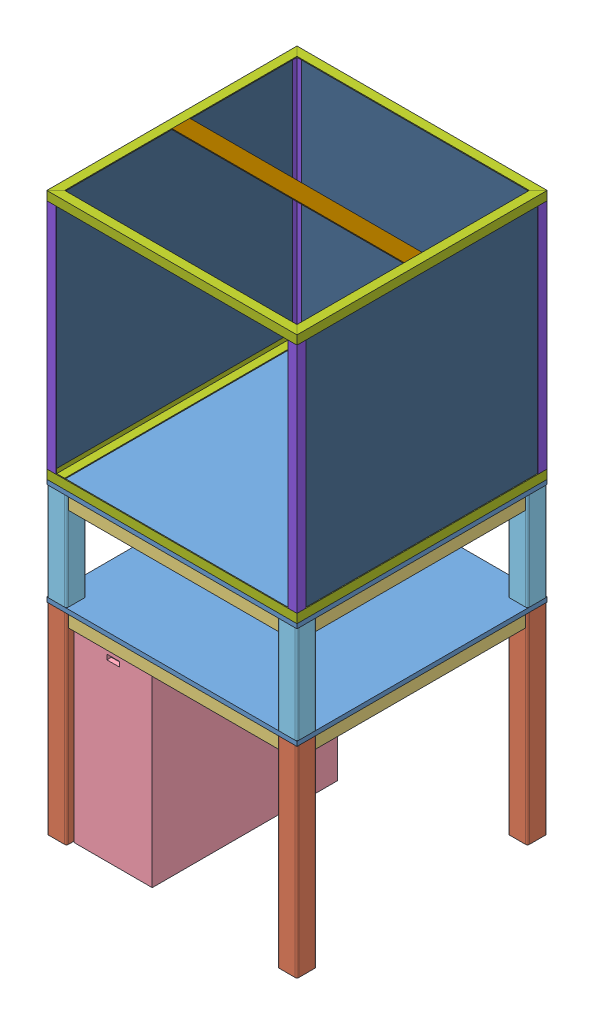
SolidWorks assembly Stolik, configuration Domyślna. Lengths in mm.
Overall size (560 1248 560).
60 component instances, 11 part files, 43 mates.
Components (placement in the parent):
- blat-1: blat [Domyślna] at (-5.6516 -3.6643 0) size (560 10 560)
- noga^Stolik-1: noga^Stolik [Domyślna] at (-5.6516 -3.6643 0) x (-1 0 0) z (0 -1 0) size (44 44 450) (virtual)
- noga^Stolik-2: noga^Stolik [Domyślna] at (-5.6516 -3.6643 0) x (0 0 -1) z (0 -1 0) size (44 44 450) (virtual)
- noga^Stolik-3: noga^Stolik [Domyślna] at (-5.6516 -3.6643 0) x (1 0 0) z (0 -1 0) size (44 44 450) (virtual)
- noga^Stolik-4: noga^Stolik [Domyślna] at (-5.6516 -3.6643 0) x (0 0 1) z (0 -1 0) size (44 44 450) (virtual)
- krokwia^Stolik-1: krokwia^Stolik [Domyślna] at (-5.6516 -3.6643 0) x (-1 0 0) z (0 -1 0) size (472 10 30) (virtual)
- krokwia^Stolik-2: krokwia^Stolik [Domyślna] at (-5.6516 -3.6643 0) x (0 0 -1) z (0 -1 0) size (472 10 30) (virtual)
- krokwia^Stolik-3: krokwia^Stolik [Domyślna] at (-5.6516 -3.6643 0) x (1 0 0) z (0 -1 0) size (472 10 30) (virtual)
- krokwia^Stolik-4: krokwia^Stolik [Domyślna] at (-5.6516 -3.6643 0) x (0 0 1) z (0 -1 0) size (472 10 30) (virtual)
- Część4^Stolik-1: Część4^Stolik [Domyślna] at (98.5779 -453.6643 -106.3674) x (-1 0 0) z (0 -1 0) size (175 415 415) (virtual)
- blat-2: blat [Domyślna] at (-5.6516 224.3357 0) size (560 10 560)
- Noga_gorna^Stolik-1: Noga_gorna^Stolik [Domyślna] at (-5.6516 224.3357 0) x (-1 0 0) z (0 -1 0) size (44 44 218) (virtual)
- Noga_gorna^Stolik-2: Noga_gorna^Stolik [Domyślna] at (-5.6516 224.3357 0) x (0 0 -1) z (0 -1 0) size (44 44 218) (virtual)
- Noga_gorna^Stolik-3: Noga_gorna^Stolik [Domyślna] at (-5.6516 224.3357 0) x (1 0 0) z (0 -1 0) size (44 44 218) (virtual)
- Noga_gorna^Stolik-4: Noga_gorna^Stolik [Domyślna] at (-5.6516 224.3357 0) x (0 0 1) z (0 -1 0) size (44 44 218) (virtual)
- krokwia^Stolik-5: krokwia^Stolik [Domyślna] at (-5.6516 224.3357 0) x (-1 0 0) z (0 -1 0) size (472 10 30) (virtual)
- krokwia^Stolik-6: krokwia^Stolik [Domyślna] at (-5.6516 224.3357 0) x (0 0 -1) z (0 -1 0) size (472 10 30) (virtual)
- krokwia^Stolik-7: krokwia^Stolik [Domyślna] at (-5.6516 224.3357 0) x (1 0 0) z (0 -1 0) size (472 10 30) (virtual)
- krokwia^Stolik-8: krokwia^Stolik [Domyślna] at (-5.6516 224.3357 0) x (0 0 1) z (0 -1 0) size (472 10 30) (virtual)
- Katownik^Stolik-1: Katownik^Stolik [Domyślna] at (-271.6516 194.3357 -236) x (0 0 1) z (0 1 0) size (20 21 15) (virtual)
- Katownik^Stolik-4: Katownik^Stolik [Domyślna] at (-241.6516 194.3357 -266) x (0 0 1) z (0 1 0) size (20 21 15) (virtual)
- Katownik^Stolik-11: Katownik^Stolik [Domyślna] at (7.5 224.3357 -266) x (0 -1 0) z (-1 0 0) size (20 21 15) (virtual)
- Katownik^Stolik-12: Katownik^Stolik [Domyślna] at (260.3484 224.3357 13.1516) x (0 -1 0) z (0 0 -1) size (20 21 15) (virtual)
- Katownik^Stolik-13: Katownik^Stolik [Domyślna] at (-18.8031 224.3357 266) x (0 -1 0) z (1 0 0) size (20 21 15) (virtual)
- Katownik^Stolik-14: Katownik^Stolik [Domyślna] at (-271.6516 224.3357 -13.1516) x (0 -1 0) z (0 0 1) size (20 21 15) (virtual)
- Katownik^Stolik-15: Katownik^Stolik [Domyślna] at (230.3484 194.3357 -266) x (-1 0 0) z (0 1 0) size (20 21 15) (virtual)
- Katownik^Stolik-16: Katownik^Stolik [Domyślna] at (260.3484 194.3357 236) x (0 0 -1) z (0 1 0) size (20 21 15) (virtual)
- Katownik^Stolik-17: Katownik^Stolik [Domyślna] at (-241.6516 194.3357 266) x (1 0 0) z (0 1 0) size (20 21 15) (virtual)
- Katownik^Stolik-18: Katownik^Stolik [Domyślna] at (260.3484 194.3357 -236) x (-1 0 0) z (0 1 0) size (20 21 15) (virtual)
- Katownik^Stolik-19: Katownik^Stolik [Domyślna] at (230.3484 194.3357 266) x (0 0 -1) z (0 1 0) size (20 21 15) (virtual)
- Katownik^Stolik-20: Katownik^Stolik [Domyślna] at (-271.6516 194.3357 236) x (1 0 0) z (0 1 0) size (20 21 15) (virtual)
- Katownik^Stolik-21: Katownik^Stolik [Domyślna] at (7.5 -3.6643 -266) x (0 -1 0) z (-1 0 0) size (20 21 15) (virtual)
- Katownik^Stolik-22: Katownik^Stolik [Domyślna] at (-271.6516 -33.6643 -236) x (0 0 1) z (0 1 0) size (20 21 15) (virtual)
- Katownik^Stolik-23: Katownik^Stolik [Domyślna] at (-241.6516 -33.6643 -266) x (0 0 1) z (0 1 0) size (20 21 15) (virtual)
- Katownik^Stolik-24: Katownik^Stolik [Domyślna] at (260.3484 -3.6643 13.1516) x (0 -1 0) z (0 0 -1) size (20 21 15) (virtual)
- Katownik^Stolik-25: Katownik^Stolik [Domyślna] at (-18.8031 -3.6643 266) x (0 -1 0) z (1 0 0) size (20 21 15) (virtual)
- Katownik^Stolik-26: Katownik^Stolik [Domyślna] at (-271.6516 -3.6643 -13.1516) x (0 -1 0) z (0 0 1) size (20 21 15) (virtual)
- Katownik^Stolik-27: Katownik^Stolik [Domyślna] at (230.3484 -33.6643 -266) x (-1 0 0) z (0 1 0) size (20 21 15) (virtual)
- Katownik^Stolik-28: Katownik^Stolik [Domyślna] at (260.3484 -33.6643 236) x (0 0 -1) z (0 1 0) size (20 21 15) (virtual)
- Katownik^Stolik-29: Katownik^Stolik [Domyślna] at (-241.6516 -33.6643 266) x (1 0 0) z (0 1 0) size (20 21 15) (virtual)
- Katownik^Stolik-30: Katownik^Stolik [Domyślna] at (260.3484 -33.6643 -236) x (-1 0 0) z (0 1 0) size (20 21 15) (virtual)
- Katownik^Stolik-31: Katownik^Stolik [Domyślna] at (230.3484 -33.6643 266) x (0 0 -1) z (0 1 0) size (20 21 15) (virtual)
- Katownik^Stolik-32: Katownik^Stolik [Domyślna] at (-271.6516 -33.6643 236) x (1 0 0) z (0 1 0) size (20 21 15) (virtual)
- Kopia Prusa MK3^Stolik-1: Kopia Prusa MK3^Stolik [Domyślna] at (-197.6615 426.9086 147.2152) x (1 0 0) z (0 1 0) size (440.6 497.98 377.63) (hidden, virtual)
- Część3^Stolik-1: Część3^Stolik [Domyślna] at origin size (20 20 560) (virtual)
- Część3^Stolik-2: Część3^Stolik [Domyślna] at (-5.6516 0 5.6516) x (0 0 1) z (-1 0 0) size (20 20 560) (virtual)
- Część3^Stolik-3: Część3^Stolik [Domyślna] at (-11.3031 0 0) x (-1 0 0) z (0 0 -1) size (20 20 560) (virtual)
- Część3^Stolik-4: Część3^Stolik [Domyślna] at (-5.6516 0 -5.6516) x (0 0 -1) z (1 0 0) size (20 20 560) (virtual)
- Część3^Stolik-5: Część3^Stolik [Domyślna] at (-5.6516 1028.6714 5.6516) x (0 0 1) z (1 0 0) size (20 20 560) (virtual)
- Część3^Stolik-6: Część3^Stolik [Domyślna] at (0 1028.6714 0) x (1 0 0) z (0 0 -1) size (20 20 560) (virtual)
- Część3^Stolik-7: Część3^Stolik [Domyślna] at (-11.3031 1028.6714 0) x (-1 0 0) z (0 0 1) size (20 20 560) (virtual)
- Część3^Stolik-8: Część3^Stolik [Domyślna] at (-5.6516 1028.6714 -5.6516) x (0 0 -1) z (-1 0 0) size (20 20 560) (virtual)
- Część5^Stolik-1: Część5^Stolik [Domyślna] at (0 254.3357 0) x (1 0 0) z (0 1 0) size (20 20 520) (virtual)
- Część5^Stolik-2: Część5^Stolik [Domyślna] at (-5.6516 254.3357 5.6516) x (0 0 1) z (0 1 0) size (20 20 520) (virtual)
- Część5^Stolik-3: Część5^Stolik [Domyślna] at (-11.3031 254.3357 0) x (-1 0 0) z (0 1 0) size (20 20 520) (virtual)
- Część5^Stolik-4: Część5^Stolik [Domyślna] at (-5.6516 254.3357 -5.6516) x (0 0 -1) z (0 1 0) size (20 20 520) (virtual)
- Część6^Stolik-1: Część6^Stolik [Domyślna] at (274.3484 1028.6714 0) x (0 0 1) z (1 0 0) size (40 2 520) (virtual)
- Część7^Stolik-1: Część7^Stolik [Domyślna] at (-283.6516 0 0) x (0 0 -1) z (1 0 0) size (528 528 4) (virtual)
- Część7^Stolik-2: Część7^Stolik [Domyślna] at (-5.6516 0 -278) size (528 528 4) (virtual)
- Część7^Stolik-3: Część7^Stolik [Domyślna] at (272.3484 0 0) x (0 0 1) z (-1 0 0) size (528 528 4) (virtual)
Mates (geometry in assembly coordinates):
- Ustalone1: in place: plane of blat-1 through (-5.6516 -3.6643 0) normal (0 -1 0); plane of ? through (0 -3.6643 0) normal (0 -1 0); moOrthogonalPlaneRef_w of blat-1 through (-5.6516 -3.6643 0) normal (0 -1 0); unknown of ?; plane of blat-1 through (-5.6516 -3.6643 0) normal (0 -1 0); line of ? through (-55 0 -3.6643) axis (0 -1 0); plane of blat-1 through (-5.6516 -3.6643 0) normal (0 -1 0); unknown of ?
- Wspólnie1: coincident aligned: plane of blat-1; plane of noga^Stolik-1
- Wspólnie2: coincident aligned: moOrthogonalPlaneRef_w of blat-1 through (-5.6516 -3.6643 0) normal (0 0 -1); plane of noga^Stolik-1
- Wspólnie3: coincident anti-aligned: moOrthogonalPlaneRef_w of blat-1 through (-5.6516 -3.6643 0) normal (1 0 0); plane of noga^Stolik-1
- Ustalone2: in place: plane of blat-1 through (-5.6516 -3.6643 0) normal (0 -1 0); plane of ? through (0 -3.6643 0) normal (0 -1 0); plane of blat-1 through (-5.6516 -3.6643 0) normal (0 -1 0); unknown of ?; plane of blat-1 through (-5.6516 -3.6643 0) normal (0 -1 0); line of ? through (-55 0 -3.6643) axis (0 -1 0); plane of blat-1 through (-5.6516 -3.6643 0) normal (0 -1 0); unknown of ?
- Wspólnie4: coincident aligned: plane of blat-1; plane of krokwia^Stolik-1
- Wspólnie5: coincident aligned: moOrthogonalPlaneRef_w of blat-1 through (-5.6516 -3.6643 0) normal (0 0 -1); plane of krokwia^Stolik-1
- Wspólnie6: coincident anti-aligned: moOrthogonalPlaneRef_w of blat-1 through (-5.6516 -3.6643 0) normal (1 0 0); plane of krokwia^Stolik-1
- Wspólnie10: coincident aligned: plane of noga^Stolik-3 through (-5.6516 -453.6643 0) normal (0 -1 0); plane of Część4^Stolik-1 through (98.5779 -453.6643 -106.3674) normal (0 -1 0)
- Równolegle1: parallel aligned: plane of noga^Stolik-2 through (-285.6516 -453.6643 -280) normal (-1 0 0); plane of Część4^Stolik-1 through (-238.9221 -38.6643 265.7916) normal (-1 0 0)
- Równolegle2: parallel anti-aligned: plane of blat-1 through (-5.6516 6.3357 0) normal (0 1 0); plane of blat-2 through (-5.6516 224.3357 0) normal (0 -1 0)
- Wspólnie13: coincident aligned: plane of blat-1 through (-285.6516 6.3357 280) normal (0 0 1); plane of blat-2 through (-285.6516 234.3357 280) normal (0 0 1)
- Odległość1: distance = 688 mm anti-aligned: plane of blat-2 through (-5.6516 234.3357 0) normal (0 1 0); plane of noga^Stolik-4 through (-5.6516 -453.6643 0) normal (0 -1 0)
- Ustalone3: in place: plane of ? through (-5.6516 284.3357 0) normal (0 -1 0); plane of ? through (0 284.3357 0) normal (0 -1 0); plane of ? through (-5.6516 284.3357 0) normal (0 -1 0); unknown of ?; plane of ? through (-5.6516 284.3357 0) normal (0 -1 0); line of ? through (-55 0 284.3357) axis (0 -1 0); plane of blat-2 through (-5.6516 224.3357 0) normal (0 -1 0); unknown of ?
- Wspólnie15: coincident aligned: plane of blat-2; plane of Noga_gorna^Stolik-1
- Wspólnie16: coincident aligned: moOrthogonalPlaneRef_w of blat-2 through (-5.6516 224.3357 0) normal (0 0 -1); plane of Noga_gorna^Stolik-1
- Wspólnie17: coincident anti-aligned: moOrthogonalPlaneRef_w of blat-2 through (-5.6516 224.3357 0) normal (1 0 0); plane of Noga_gorna^Stolik-1
- Wspólnie19: coincident anti-aligned: plane of Noga_gorna^Stolik-1 through (-241.6516 -55.8897 240) normal (1 0 0); plane of krokwia^Stolik-5 through (-241.6516 194.3357 276) normal (-1 0 0)
- Wspólnie20: coincident anti-aligned: plane of blat-2 through (-5.6516 224.3357 0) normal (0 -1 0); plane of krokwia^Stolik-5 through (-5.6516 224.3357 0) normal (0 1 0)
- Wspólnie21: coincident anti-aligned: plane of Noga_gorna^Stolik-2 through (-245.6516 -55.8897 -236) normal (0 0 1); plane of Katownik^Stolik-1 through (-270.6516 194.3357 -236) normal (0 0 -1)
- Wspólnie23: coincident aligned: plane of krokwia^Stolik-6 through (-5.6516 194.3357 0) normal (0 -1 0); plane of Katownik^Stolik-1 through (-270.6516 194.3357 -236) normal (0 -1 0)
- Wspólnie30: coincident anti-aligned: plane of krokwia^Stolik-7 through (230.3484 194.3357 -266) normal (0 0 1); plane of Katownik^Stolik-4 through (-240.6516 194.3357 -266) normal (0 0 -1)
- Wspólnie31: coincident anti-aligned: plane of Noga_gorna^Stolik-2 through (-241.6516 -55.8897 -276) normal (1 0 0); plane of Katownik^Stolik-4 through (-241.6516 201.8357 -254) normal (-1 0 0)
- Wspólnie32: coincident aligned: plane of krokwia^Stolik-7 through (-5.6516 194.3357 0) normal (0 -1 0); plane of Katownik^Stolik-4 through (-240.6516 194.3357 -266) normal (0 -1 0)
- Wspólnie41: coincident anti-aligned: plane of krokwia^Stolik-7 through (230.3484 194.3357 -266) normal (0 0 1); plane of Katownik^Stolik-11 through (0 212.3357 -266) normal (0 0 -1)
- Wspólnie42: coincident anti-aligned: plane of blat-2 through (-5.6516 224.3357 0) normal (0 -1 0); plane of Katownik^Stolik-11 through (7.5 224.3357 -265) normal (0 1 0)
- Wspólnie43: coincident: moEndPointRef_w of Katownik^Stolik-11; plane of assembly
- Wspólnie44: coincident anti-aligned: plane of noga^Stolik-3 through (274.3484 -453.6643 -236) normal (0 0 1); plane of krokwia^Stolik-8 through (270.3484 194.3357 -236) normal (0 0 -1)
- Wspólnie46: coincident: point of Noga_gorna^Stolik-1; point of krokwia^Stolik-5
- Wspólnie47: coincident anti-aligned: plane of krokwia^Stolik-6 through (-271.6516 194.3357 -236) normal (1 0 0); plane of Katownik^Stolik-1 through (-271.6516 201.8357 -224) normal (-1 0 0)
- Równolegle3: parallel aligned: plane of blat-2 through (-5.6516 234.3357 0) normal (0 1 0); plane of Kopia Prusa MK3^Stolik-1 through (-140.314 307.9936 144.4526) normal (0 1 0)
- Ustalone4: in place: plane of Część3^Stolik-1 through (-285.6516 264.3357 -280) normal (0 1 0); plane of ? through (0 264.3357 0) normal (0 1 0); plane of Część3^Stolik-1 through (-285.6516 264.3357 -280) normal (0 1 0); plane of ? through (0 264.3357 0) normal (0 0 -1); plane of Część3^Stolik-1 through (-285.6516 264.3357 -280) normal (0 1 0); line of ? through (-55 0 264.3357) axis (0 1 0); plane of Część3^Stolik-1 through (-285.6516 254.3357 -280) normal (0 1 0); unknown of Część5^Stolik-1
- Wspólnie50: coincident aligned: plane of Część3^Stolik-1; plane of Część5^Stolik-1
- Wspólnie51: coincident aligned: moOrthogonalPlaneRef_w of Część3^Stolik-1 through (0 254.3357 0) normal (0 0 -1); plane of Część5^Stolik-1 through (0 254.3357 0) normal (0 0 -1)
- Wspólnie52: coincident anti-aligned: moOrthogonalPlaneRef_w of Część3^Stolik-1 through (0 254.3357 0) normal (-1 0 0); plane of Część5^Stolik-1
- Ustalone5: in place: plane of Część3^Stolik-7 through (274.3484 794.3357 -280) normal (1 0 0); plane of ? through (274.3484 0 0) normal (1 0 0); plane of Część3^Stolik-7 through (274.3484 794.3357 -280) normal (1 0 0); line of ? through (-55 274.3484 0) axis (0 0 1); plane of Część3^Stolik-7 through (274.3484 794.3357 -280) normal (1 0 0); plane of ? through (274.3484 0 0) normal (0 0 -1); plane of Część3^Stolik-7 through (274.3484 794.3357 -280) normal (1 0 0); unknown of Część6^Stolik-1
- Wspólnie53: coincident aligned: plane of Część3^Stolik-7; plane of Część6^Stolik-1
- Wspólnie54: coincident aligned: moOrthogonalPlaneRef_w of Część3^Stolik-7 through (274.3484 1028.6714 0) normal (0 -1 0); plane of Część6^Stolik-1
- Wspólnie55: coincident anti-aligned: moOrthogonalPlaneRef_w of Część3^Stolik-7 through (274.3484 1028.6714 0) normal (0 0 -1); plane of Część6^Stolik-1
- Ustalone6: in place: plane of Część3^Stolik-1 through (-283.6516 254.3357 -280) normal (1 0 0); plane of Część7^Stolik-1 through (-283.6516 0 0) normal (1 0 0); plane of Część3^Stolik-1 through (-283.6516 254.3357 -280) normal (1 0 0); line of Część7^Stolik-1 through (-55 -283.6516 0) axis (0 0 1); plane of Część3^Stolik-1 through (-283.6516 254.3357 -280) normal (1 0 0); plane of Część7^Stolik-1 through (-283.6516 0 0) normal (0 0 -1); plane of Część3^Stolik-1 through (-283.6516 254.3357 -280) normal (1 0 0); unknown of Część7^Stolik-1
- Wspólnie56: coincident aligned: plane of Część3^Stolik-1; plane of Część7^Stolik-1
- Wspólnie57: coincident aligned: moOrthogonalPlaneRef_w of Część3^Stolik-1 through (-283.6516 0 0) normal (0 1 0); plane of Część7^Stolik-1
- Wspólnie58: coincident anti-aligned: moOrthogonalPlaneRef_w of Część3^Stolik-1 through (-283.6516 0 0) normal (0 0 1); plane of Część7^Stolik-1 through (-283.6516 0 0) normal (0 0 -1)
